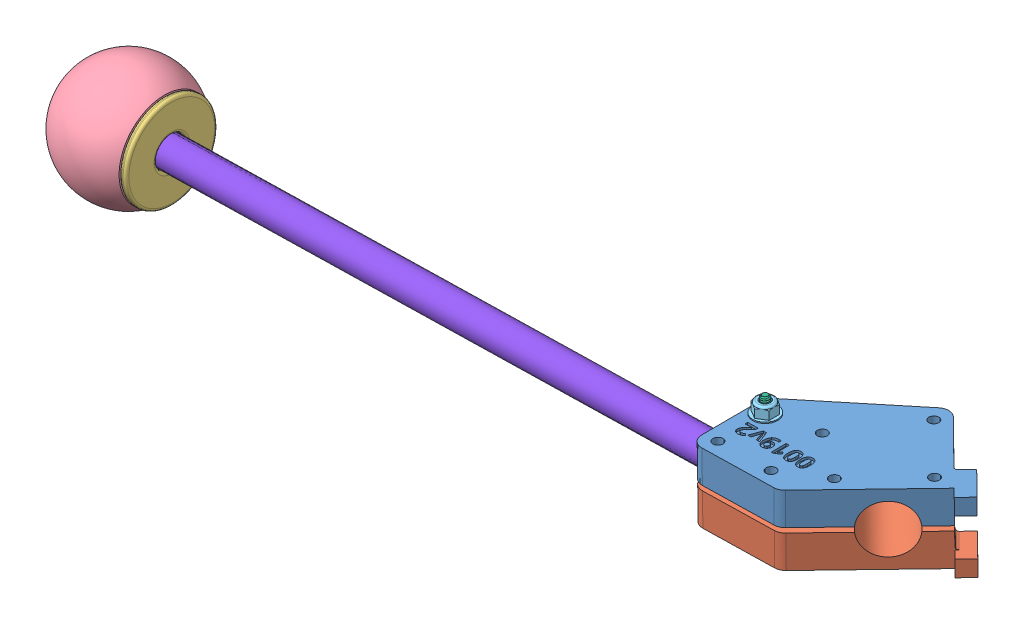
SolidWorks assembly landing_leg_assy, configuration Default. Lengths in mm.
Overall size (369.94 52.08 78.3).
8 component instances, 8 part files, 14 mates.
Components (placement in the parent):
- Knee_B-1: Knee_B [默认] at (317.0498 384.158 -52.2431) x (0.999858 0.015698 -0.006175) z (0.006154 0.001386 0.99998) size (84.73 14 66.95)
- Knee_A-1: Knee_A [默认] at (317.0498 384.158 -52.2431) x (0.999858 0.015698 -0.006175) z (0.006154 0.001386 0.99998) size (84.73 14 66.95)
- Leg_End Cap-1: Leg_End Cap [默认] at (467.0284 386.5127 -53.1693) x (0.999858 0.015698 -0.006175) z (0.006175 0.000048 0.999981) size (23.66 40 40)
- Leg_Foam_Ball-1: Leg_Foam_Ball [默认] at (467.0284 386.5127 -53.1693) x (0.999858 0.015698 -0.006175) z (0.006175 0.000048 0.999981) size (50.8 50.8 50.8)
- Nut_6-32 thread, lock, flange-1: Nut_6-32 thread, lock, flange [默认] at (281.7266 398.5919 -62.3959) x (0.999877 0.015706 -0.000184) z (0.000163 0.001292 0.999999) size (10.72 5.16 10.72)
- Screw_shc_6-32 thread_1.5 in ling-1: Screw_shc_6-32 thread_1.5 in ling [默认] at (281.6153 405.675 -62.4051) x (0.999877 0.015706 -0.00001) z (-0.015706 0.999876 -0.001289) size (5.74 5.74 41.62)
- wahser_#6-1: wahser_#6 [默认] at (282.2137 367.5797 -62.356) x (0.999877 0.015706 -0.00001) z (-0.00001 0.001289 0.999999) size (7.92 1.02 7.92)
- Leg Tube-2: Leg Tube [默认] at (467.0284 386.5127 -53.1693) x (0.999858 0.015698 -0.006175) z (0.006188 -0.000789 0.999981) size (300 12.7 12.7)
Mates (geometry in assembly coordinates):
- 同心1: concentric aligned: cylinder of Leg_End Cap-1 through (12.0919 379.37 -50.3598) axis (0.999858 0.015698 -0.006175) radius 9.652; cylinder of Leg_Foam_Ball-1 through (32.7478 379.6943 -50.4874) axis (0.999858 0.015698 -0.006175) radius 9.652
- 重合1: coincident anti-aligned: plane of Leg_End Cap-1 through (11.9616 387.751 -50.3594) normal (-0.999858 -0.015698 0.006175); plane of Leg_Foam_Ball-1 through (12.0932 379.3701 -50.3598) normal (0.999858 0.015698 -0.006175)
- 同心2: concentric aligned: cylinder of Leg_End Cap-1 through (12.0919 379.37 -50.3598) axis (0.999858 0.015698 -0.006175) radius 6.477; cylinder of Leg Tube-2 through (17.0925 379.4486 -50.3907) axis (0.999858 0.015698 -0.006175) radius 6.35
- 重合2: coincident anti-aligned: plane of Leg_End Cap-1 through (17.0925 379.4486 -50.3907) normal (0.999858 0.015698 -0.006175); plane of Leg Tube-2 through (16.9928 385.7978 -50.3851) normal (-0.999858 -0.015698 0.006175)
- 同心4: concentric anti-aligned: cylinder of Knee_B-1 through (317.0498 384.158 -52.2431) axis (-0.999858 -0.015698 0.006175) radius 6.35; cylinder of Leg Tube-2 through (17.0925 379.4486 -50.3907) axis (0.999858 0.015698 -0.006175) radius 6.35
- 重合3: coincident anti-aligned: plane of Knee_B-1 through (317.0498 384.158 -52.2431) normal (-0.999858 -0.015698 0.006175); plane of Leg Tube-2 through (316.9641 389.6183 -52.2383) normal (0.999858 0.015698 -0.006175)
- 重合4: coincident anti-aligned: plane of Knee_A-1 through (317.0498 384.158 -52.2431) normal (-0.999858 -0.015698 0.006175); plane of Leg Tube-2 through (316.9641 389.6183 -52.2383) normal (0.999858 0.015698 -0.006175)
- 同心5: concentric anti-aligned: cylinder of Knee_A-1 through (317.0498 384.158 -52.2431) axis (-0.999858 -0.015698 0.006175) radius 6.35; cylinder of Leg Tube-2 through (17.0925 379.4486 -50.3907) axis (0.999858 0.015698 -0.006175) radius 6.35
- 重合6: coincident anti-aligned: plane of Knee_B-1 through (316.8142 399.1561 -52.2624) normal (-0.015706 0.999876 -0.001289); plane of Nut_6-32 thread, lock, flange-1 through (281.7258 398.586 -66.9787) normal (0.015706 -0.999876 0.001289)
- 同心6: concentric aligned: cylinder of Knee_B-1 through (281.7266 398.5919 -62.3959) axis (-0.015706 0.999876 -0.001289) radius 2.159; cylinder of Nut_6-32 thread, lock, flange-1 through (281.6455 403.7506 -62.4026) axis (-0.015706 0.999876 -0.001289) radius 2.2596
- 重合7: coincident anti-aligned: plane of Knee_A-1 through (317.2854 369.1598 -52.2238) normal (0.015706 -0.999876 0.001289); plane of wahser_#6-1 through (286.1597 368.6578 -62.3573) normal (-0.015706 0.999876 -0.001289)
- 同心7: concentric aligned: cylinder of Knee_A-1 through (282.1977 368.5956 -62.3573) axis (0.015706 -0.999876 0.001289) radius 2.159; cylinder of wahser_#6-1 through (282.1977 368.5956 -62.3573) axis (0.015706 -0.999876 0.001289) radius 1.9812
- 同心8: concentric anti-aligned: cylinder of Screw_shc_6-32 thread_1.5 in ling-1 through (282.2137 367.5797 -62.356) axis (-0.015706 0.999876 -0.001289) radius 1.7526; cylinder of wahser_#6-1 through (282.1977 368.5956 -62.3573) axis (0.015706 -0.999876 0.001289) radius 1.9812
- 重合8: coincident anti-aligned: plane of Screw_shc_6-32 thread_1.5 in ling-1 through (282.2137 367.5797 -62.356) normal (-0.015706 0.999876 -0.001289); plane of wahser_#6-1 through (284.1947 367.6109 -62.356) normal (0.015706 -0.999876 0.001289)
